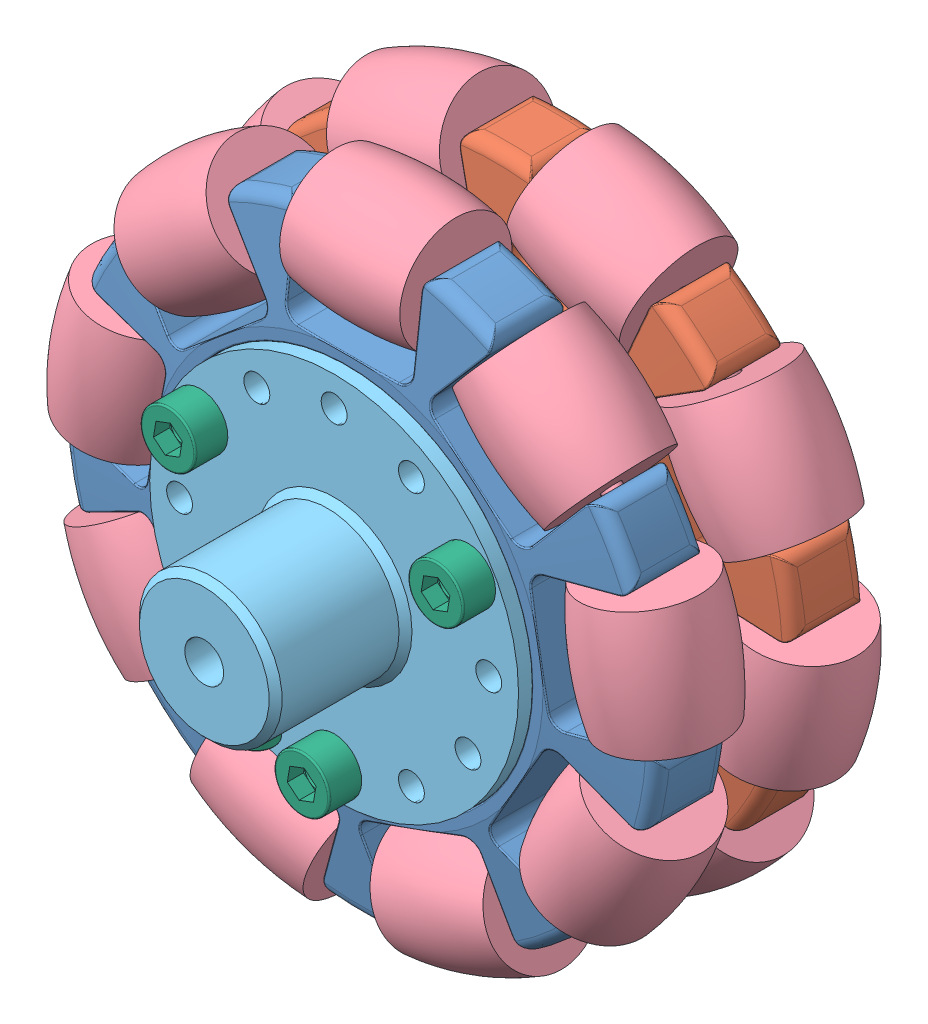
SolidWorks assembly banhxe, configuration Default. Lengths in mm.
Overall size (124.48 124.98 61.51).
29 component instances, 7 part files, 22 mates.
Components (placement in the parent):
- omniwheel_1-1: omniwheel_1 [Default] at (-17.0114 53.5739 73.2518) size (91.98 90.63 15.09)
- omniwheel_2-1: omniwheel_2 [Default] at (-17.0114 53.5739 37.2518) x (-0.5 -0.866025 0) z (0 0 -1) size (91.98 90.63 15.09)
- Part1^banhxe-1: Part1^banhxe [Default] at (-17.0114 53.5739 59.2518) x (-1 0 0) z (0 0 -1) size (56.8 56.8 18) (virtual)
- roller-1: roller [Default] at (-17.0114 132.3987 78.8462) x (1 0 0) z (0 0.323318 -0.94629) size (24.1 19 19)
- roller-3: roller [Default] at (33.6561 113.9572 78.8462) x (0.766044 -0.642788 0) z (0.207825 0.247676 -0.94629) size (24.1 19 19)
- roller-4: roller [Default] at (60.6158 67.2617 78.8462) x (0.173648 -0.984808 0) z (0.318406 0.056144 -0.94629) size (24.1 19 19)
- roller-5: roller [Default] at (51.2528 14.1616 78.8462) x (-0.5 -0.866025 0) z (0.280001 -0.161659 -0.94629) size (24.1 19 19)
- roller-6: roller [Default] at (9.9482 -20.4971 78.8462) x (-0.939693 -0.34202 0) z (0.110581 -0.303819 -0.94629) size (24.1 19 19)
- roller-7: roller [Default] at (-43.9711 -20.4971 78.8462) x (-0.939693 0.34202 0) z (-0.110581 -0.303819 -0.94629) size (24.1 19 19)
- roller-8: roller [Default] at (-85.2757 14.1616 78.8462) x (-0.5 0.866025 0) z (-0.280001 -0.161659 -0.94629) size (24.1 19 19)
- roller-9: roller [Default] at (-94.6387 67.2617 78.8462) x (0.173648 0.984808 0) z (-0.318406 0.056144 -0.94629) size (24.1 19 19)
- roller-10: roller [Default] at (-67.679 113.9572 78.8462) x (0.766044 0.642788 0) z (-0.207825 0.247676 -0.94629) size (24.1 19 19)
- roller-11: roller [Default] at (-17.5454 53.8822 51.7918) x (0.5 0.866025 0) z (-0.150538 0.086913 0.984776) size (24.1 19 19)
- roller-12: roller [Default] at (-17.6186 53.4669 51.7918) x (-0.173648 0.984808 0) z (-0.171186 -0.030185 0.984776) size (24.1 19 19)
- roller-13: roller [Default] at (-17.4078 53.1016 51.7918) x (-0.766044 0.642788 0) z (-0.111734 -0.133159 0.984776) size (24.1 19 19)
- roller-14: roller [Default] at (-17.0114 52.9574 51.7918) x (-1 0 0) z (0 -0.173827 0.984776) size (24.1 19 19)
- roller-15: roller [Default] at (-16.6151 53.1016 51.7918) x (-0.766044 -0.642788 0) z (0.111734 -0.133159 0.984776) size (24.1 19 19)
- roller-16: roller [Default] at (-16.4042 53.4669 51.7918) x (-0.173648 -0.984808 0) z (0.171186 -0.030185 0.984776) size (24.1 19 19)
- roller-17: roller [Default] at (-16.4775 53.8822 51.7918) x (0.5 -0.866025 0) z (0.150538 0.086913 0.984776) size (24.1 19 19)
- roller-18: roller [Default] at (-16.8006 54.1533 51.7918) x (0.939693 -0.34202 0) z (0.059452 0.163344 0.984776) size (24.1 19 19)
- roller-19: roller [Default] at (-17.2223 54.1533 51.7918) x (0.939693 0.34202 0) z (-0.059452 0.163344 0.984776) size (24.1 19 19)
- Part3^banhxe-1: Part3^banhxe [Default] at (-17.0114 53.5739 72.2518) size (56.8 56.8 23)
- socket head cap screw_iso-2: socket head cap screw_iso [ISO 4762 M5 x 40 - 22C] at (-37.6228 65.4739 80.2518) x (0 0 -1) z (-0.98661 0.163099 0) size (45 8.5 8.5)
- hex nut gradec_iso-1: hex nut gradec_iso [ISO - 4034 - M5 - N] at (-37.6228 65.4739 36.6518) x (0 -1 0) z (0 0 -1) size (8 9.24 5.6)
- hex nut gradec_iso-2: hex nut gradec_iso [ISO - 4034 - M5 - N] at (-17.0114 29.7739 36.6518) x (0.866025 0.5 0) z (0 0 -1) size (8 9.24 5.6)
- hex nut gradec_iso-3: hex nut gradec_iso [ISO - 4034 - M5 - N] at (3.6 65.4739 36.6518) x (-0.866025 0.5 0) z (0 0 -1) size (8 9.24 5.6)
- socket head cap screw_iso-3: socket head cap screw_iso [ISO 4762 M5 x 40 - 22C] at (-17.0114 29.7739 80.2518) x (0 0 -1) z (0.352057 -0.935979 0) size (45 8.5 8.5)
- socket head cap screw_iso-4: socket head cap screw_iso [ISO 4762 M5 x 40 - 22C] at (3.6 65.4739 80.2518) x (0 0 -1) z (0.634553 0.77288 0) size (45 8.5 8.5)
- socket head cap screw_iso-7: socket head cap screw_iso [ISO 4762 M3 x 10 - 10C] at (-17.0114 39.5739 87.2518) x (0 1 0) z (-0.678428 0 0.734667) size (13 5.5 5.5)
Mates (geometry in assembly coordinates):
- Concentric1: concentric: cylinder of omniwheel_1-1 through (-17.0114 53.5739 65.7518) axis (0 0 1) radius 14; cylinder of omniwheel_2-1 through (-17.0114 53.5739 44.7518) axis (0 0 -1) radius 14
- Concentric2: concentric: circle of omniwheel_1-1; circle of omniwheel_2-1
- InPlace1: in place: plane of omniwheel_1-1 through (-17.0114 47.6916 59.2518) normal (0 0 -1); plane of ? through (0 0 59.2518) normal (0 0 -1); moOrthogonalPlaneRef_w of omniwheel_1-1 through (-17.0114 47.6916 59.2518) normal (0 0 -1); unknown of ?; plane of omniwheel_1-1 through (-17.0114 47.6916 59.2518) normal (0 0 -1); plane of ? through (0 0 59.2518) normal (-1 0 0); plane of omniwheel_1-1 through (-17.0114 47.6916 59.2518) normal (0 0 -1); unknown of Part1^banhxe-1
- Coincident1: coincident: plane of omniwheel_1-1; plane of Part1^banhxe-1
- Coincident2: coincident: moOrthogonalPlaneRef_w of omniwheel_1-1 through (-17.0114 53.5739 59.2518) normal (0 1 0); plane of Part1^banhxe-1 through (-17.0114 53.5739 59.2518) normal (0 1 0)
- Coincident3: coincident: moOrthogonalPlaneRef_w of omniwheel_1-1 through (-17.0114 53.5739 59.2518) normal (1 0 0); plane of Part1^banhxe-1 through (-17.0114 53.5739 59.2518) normal (-1 0 0)
- Concentric3: concentric: cylinder of omniwheel_1-1 through (-7.2614 94.0739 65.7518) axis (-1 0 0) radius 1.5; cylinder of roller-1 through (-26.2614 94.0739 65.7518) axis (-1 0 0) radius 1.4
- Width1: width: plane of omniwheel_1-1 through (-26.7614 47.6916 65.7518) normal (1 0 0); plane of omniwheel_1-1 through (-7.2614 47.6916 65.7518) normal (-1 0 0); plane of roller-1 through (-26.2614 85.9009 62.9593) normal (-1 0 0); plane of roller-1 through (-7.7614 85.9009 62.9593) normal (1 0 0)
- Concentric4: concentric: cylinder of omniwheel_2-1 through (-47.2105 82.2677 44.7518) axis (-0.5 -0.866025 0) radius 1.5; cylinder of roller-11 through (-56.7105 65.8132 44.7518) axis (-0.5 -0.866025 0) radius 1.4
- Width2: width: plane of omniwheel_2-1 through (-16.7921 42.189 44.7518) normal (0.5 0.866025 0); plane of omniwheel_2-1 through (-7.0421 59.0765 44.7518) normal (-0.5 -0.866025 0); plane of roller-11 through (-64.0764 70.0659 43.2505) normal (-0.5 -0.866025 0); plane of roller-11 through (-54.8264 86.0874 43.2505) normal (0.5 0.866025 0)
- Coincident5: coincident: plane of omniwheel_2-1 through (-11.9171 50.6327 51.2518) normal (0 0 1); plane of Part1^banhxe-1 through (-17.0114 53.5739 51.2518) normal (0 0 -1)
- InPlace2: in place: plane of omniwheel_1-1 through (-17.0114 47.6916 72.2518) normal (0 0 1); plane of ? through (0 0 72.2518) normal (0 0 1); plane of omniwheel_1-1 through (-17.0114 47.6916 72.2518) normal (0 0 1); plane of ? through (0 0 72.2518) normal (0 1 0); plane of omniwheel_1-1 through (-17.0114 47.6916 72.2518) normal (0 0 1); plane of ? through (0 0 72.2518) normal (1 0 0); plane of omniwheel_1-1 through (-17.0114 47.6916 72.2518) normal (0 0 1); unknown of Part3^banhxe-1
- Coincident6: coincident: plane of omniwheel_1-1; plane of Part3^banhxe-1
- Coincident7: coincident: moOrthogonalPlaneRef_w of omniwheel_1-1 through (-17.0114 53.5739 72.2518) normal (0 1 0); plane of Part3^banhxe-1 through (-17.0114 53.5739 72.2518) normal (0 1 0)
- Coincident8: coincident: moOrthogonalPlaneRef_w of omniwheel_1-1 through (-17.0114 53.5739 72.2518) normal (-1 0 0); plane of Part3^banhxe-1 through (-17.0114 53.5739 72.2518) normal (1 0 0)
- Concentric6: concentric: cylinder of Part3^banhxe-1 through (-37.6228 65.4739 72.2518) axis (0 0 1) radius 2; cylinder of socket head cap screw_iso-2 through (-37.6228 65.4739 112.0018) axis (0 0 1) radius 4.25
- Coincident7: coincident: plane of Part3^banhxe-1 through (-17.0114 53.5739 75.2518) normal (0 0 1); plane of socket head cap screw_iso-2 through (-38.316 61.2808 75.2518) normal (0 0 -1)
- Concentric7: concentric: cylinder of omniwheel_2-1 through (-37.6228 65.4739 42.2518) axis (0 0 -1) radius 2.5; cylinder of hex nut gradec_iso-1 through (-37.6228 65.4739 61.6893) axis (0 0 -1) radius 2.5
- Coincident9: coincident: plane of omniwheel_2-1 through (-35.2557 69.5739 42.2518) normal (0 0 -1); plane of hex nut gradec_iso-1 through (-42.2416 65.4739 42.2518) normal (0 0 1)
- Parallel2: parallel: plane of omniwheel_2-1 through (-42.3571 65.4739 42.2518) normal (0.866025 -0.5 0); plane of hex nut gradec_iso-1 through (-42.2416 65.4739 42.2518) normal (-0.866025 0.5 0)
- Concentric9: concentric: cylinder of Part3^banhxe-1 through (-17.0114 38.5739 87.2518) axis (0 1 0) radius 2; cylinder of socket head cap screw_iso-7 through (-17.0114 7.8239 87.2518) axis (0 -1 0) radius 2.75
- Tangent1: tangent: cylinder of Part3^banhxe-1 through (-17.0114 53.5739 95.2518) axis (0 0 -1) radius 11; plane of socket head cap screw_iso-7 through (-19.0318 42.5739 85.3861) normal (0 1 0)
